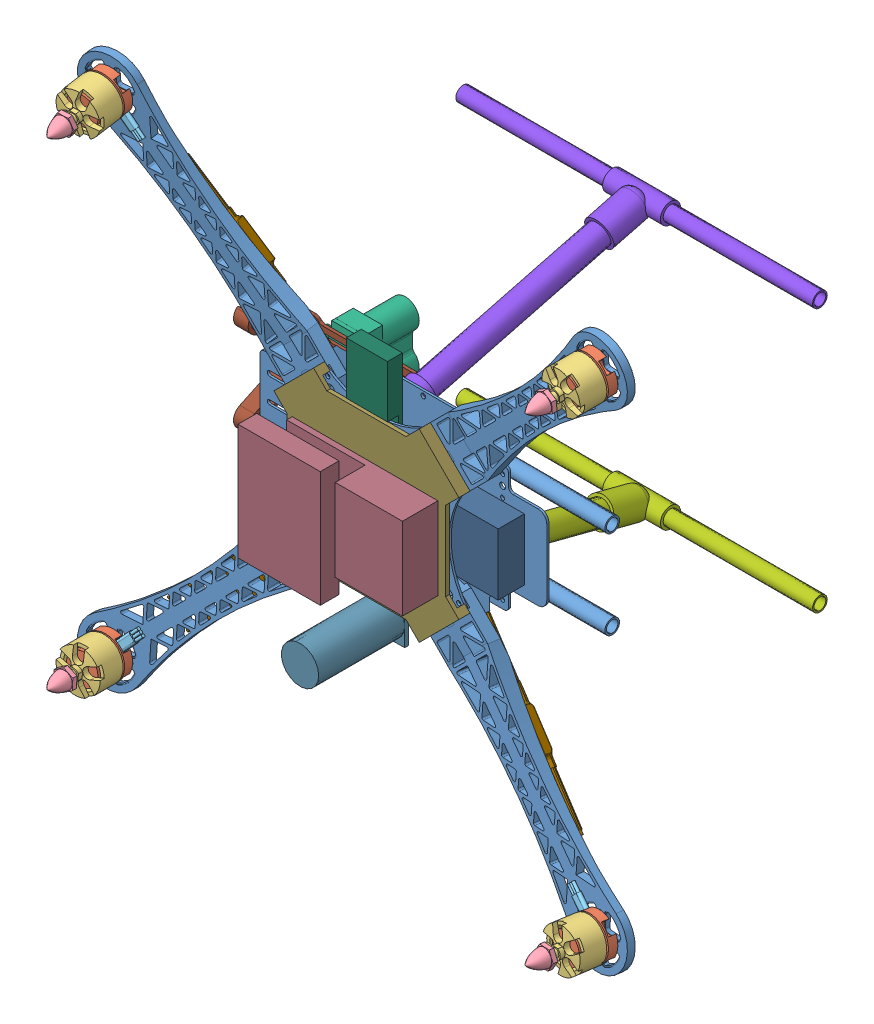
SolidWorks assembly Complete Drone Gazebo, configuration Default. Lengths in mm.
Overall size (374.52 411.37 390.68).
34 component instances, 15 part files, 50 mates.
Components (placement in the parent):
- S500 Frame-1: S500 Frame [Default] at (72.5801 224.1097 294.7299) size (374.52 374.52 61.06)
- User Library-emaxmodel-mt2213-1: User Library-emaxmodel-mt2213 [По умолчанию] at (238.5265 390.0562 331.8046) x (0.997236 0.002051 0.074267) z (0.007529 -0.997263 -0.073557) size (36.98 47 36.98)
  - User Library-emaxmodel-mt2213_emaxmodel-mt2213-stator-1: User Library-emaxmodel-mt2213_emaxmodel-mt2213-stator [По умолчанию] at origin size (28 21 28)
  - User Library-emaxmodel-mt2213_emaxmodel-mt2213-rotor-1: User Library-emaxmodel-mt2213_emaxmodel-mt2213-rotor [По умолчанию] at (0 7 0) x (0.999557 0 0.02976) z (-0.02976 0 0.999557) size (28 32 28)
  - User Library-emaxmodel-mt2213_emaxmodel-mt2213-cone-1: User Library-emaxmodel-mt2213_emaxmodel-mt2213-cone [По умолчанию] at (0 32 0) size (12 15 13.86)
  - User Library-emaxmodel-mt2213_wires-1: User Library-emaxmodel-mt2213_wires [По умолчанию] at (-15.8508 1.5 15.8508) x (0.707107 0 0.707107) z (-0.707107 0 0.707107) size (7 3 19)
- User Library-emaxmodel-mt2213-2: User Library-emaxmodel-mt2213 [По умолчанию] at (-93.3664 58.1632 331.8046) x (-0.996096 -0.042797 0.07721) z (-0.048269 0.996346 -0.070461) size (36.98 47 36.98)
  - User Library-emaxmodel-mt2213_emaxmodel-mt2213-stator-1: User Library-emaxmodel-mt2213_emaxmodel-mt2213-stator [По умолчанию] at origin size (28 21 28)
  - User Library-emaxmodel-mt2213_emaxmodel-mt2213-rotor-1: User Library-emaxmodel-mt2213_emaxmodel-mt2213-rotor [По умолчанию] at (0 7 0) x (0.999557 0 0.02976) z (-0.02976 0 0.999557) size (28 32 28)
  - User Library-emaxmodel-mt2213_emaxmodel-mt2213-cone-1: User Library-emaxmodel-mt2213_emaxmodel-mt2213-cone [По умолчанию] at (0 32 0) size (12 15 13.86)
  - User Library-emaxmodel-mt2213_wires-1: User Library-emaxmodel-mt2213_wires [По умолчанию] at (-15.8508 1.5 15.8508) x (0.707107 0 0.707107) z (-0.707107 0 0.707107) size (7 3 19)
- User Library-emaxmodel-mt2213-3: User Library-emaxmodel-mt2213 [По умолчанию] at (-93.3664 390.0562 331.8046) x (0.025833 0.997057 0.072181) z (0.99693 -0.020357 -0.075605) size (36.98 47 36.98)
  - User Library-emaxmodel-mt2213_emaxmodel-mt2213-stator-1: User Library-emaxmodel-mt2213_emaxmodel-mt2213-stator [По умолчанию] at origin size (28 21 28)
  - User Library-emaxmodel-mt2213_emaxmodel-mt2213-rotor-1: User Library-emaxmodel-mt2213_emaxmodel-mt2213-rotor [По умолчанию] at (0 7 0) x (0.999557 0 0.02976) z (-0.02976 0 0.999557) size (28 32 28)
  - User Library-emaxmodel-mt2213_emaxmodel-mt2213-cone-1: User Library-emaxmodel-mt2213_emaxmodel-mt2213-cone [По умолчанию] at (0 32 0) size (12 15 13.86)
  - User Library-emaxmodel-mt2213_wires-1: User Library-emaxmodel-mt2213_wires [По умолчанию] at (-15.8508 1.5 15.8508) x (0.707107 0 0.707107) z (-0.707107 0 0.707107) size (7 3 19)
- User Library-emaxmodel-mt2213-4: User Library-emaxmodel-mt2213 [По умолчанию] at (238.5265 58.1632 331.8046) x (0.007659 -0.997178 0.074679) z (-0.997235 -0.013136 -0.073138) size (36.98 47 36.98)
  - User Library-emaxmodel-mt2213_emaxmodel-mt2213-stator-1: User Library-emaxmodel-mt2213_emaxmodel-mt2213-stator [По умолчанию] at origin size (28 21 28)
  - User Library-emaxmodel-mt2213_emaxmodel-mt2213-rotor-1: User Library-emaxmodel-mt2213_emaxmodel-mt2213-rotor [По умолчанию] at (0 7 0) x (0.999557 0 0.02976) z (-0.02976 0 0.999557) size (28 32 28)
  - User Library-emaxmodel-mt2213_emaxmodel-mt2213-cone-1: User Library-emaxmodel-mt2213_emaxmodel-mt2213-cone [По умолчанию] at (0 32 0) size (12 15 13.86)
  - User Library-emaxmodel-mt2213_wires-1: User Library-emaxmodel-mt2213_wires [По умолчанию] at (-15.8508 1.5 15.8508) x (0.707107 0 0.707107) z (-0.707107 0 0.707107) size (7 3 19)
- User Library-LIDAR-Lite_v3-1: User Library-LIDAR-Lite_v3 [Default] at (-16.6199 221.1097 248.205) x (0 -1 0) z (0 0 -1) size (48.5 35.6 40)
- Drone Legs-1: Drone Legs [Default] at (195.2301 134.5438 138.1528) x (0 -0.967884 0.251398) z (-1 0 0) size (19.56 171.15 242.57)
- Drone Legs Right-1: Drone Legs Right [Default] at (195.2301 313.6756 138.1528) x (0 -0.967884 -0.251398) z (-1 0 0) size (19.56 171.15 242.57)
- 30A ESC-1: 30A ESC [Default] at (166.8316 147.9576 305.3085) x (0.707107 0.707107 0) z (0.69963 -0.69963 0.145038) size (28.83 9.95 119.13)
- 30A ESC-2: 30A ESC [Default] at (-3.8513 129.5788 305.3664) x (0.707107 -0.707107 0) z (-0.69963 -0.69963 0.145038) size (28.83 9.95 119.13)
- 30A ESC-3: 30A ESC [Default] at (-4.7202 319.5053 311.4505) x (0.707107 0.707107 0) z (-0.69963 0.69963 0.145038) size (28.83 9.95 119.13)
- 30A ESC-4: 30A ESC [Default] at (167.8781 301.3124 311.4303) x (0.707107 -0.707107 0) z (0.69963 0.69963 0.145038) size (28.83 9.95 119.13)
- LiPO Battery-1: LiPO Battery [Default] at (83.8871 224.0547 296.2299) size (136.91 41.91 17.78)
- S500 Frame - Copy-1: S500 Frame - Copy [Default] at (-56.5902 224.1097 294.7299) size (100 71.1 41.02)
- Gazebo Drone Mount-1: Gazebo Drone Mount [Default] at (72.5801 224.039 323.8499) x (-0.707107 0.707107 0) z (0 0 -1) size (139.7 139.7 7.62)
- Electronics gazebo-1: Electronics gazebo [Default] at (71.6753 223.0343 323.8499) x (0 -1 0) z (0 0 1) size (78.74 101.6 34.29)
- RTK  Antennae Gazebo-1: RTK  Antennae Gazebo [Default] at (76.7679 163.0462 312.1899) x (-1 0 0) z (0 0 1) size (25.4 38.1 60.96)
- Gazebo xbee-1: Gazebo xbee [Default] at (71.4223 291.4188 312.1899) size (27.94 45.72 10.16)
Mates (geometry in assembly coordinates):
- Concentric8: concentric aligned: circle of S500 Frame-1; circle of User Library-emaxmodel-mt2213-3/User Library-emaxmodel-mt2213_emaxmodel-mt2213-stator-1
- Coincident4: coincident anti-aligned: plane of S500 Frame-1 through (-121.5693 391.389 333.9997) normal (0.073913 -0.073913 0.994522); plane of User Library-emaxmodel-mt2213-3/User Library-emaxmodel-mt2213_emaxmodel-mt2213-stator-1 through (-93.3664 390.0562 331.8046) normal (-0.073913 0.073913 -0.994522)
- Concentric9: concentric aligned: circle of S500 Frame-1; circle of User Library-emaxmodel-mt2213-1/User Library-emaxmodel-mt2213_emaxmodel-mt2213-stator-1
- Coincident5: coincident anti-aligned: plane of S500 Frame-1 through (239.8594 418.2591 333.9997) normal (-0.073913 -0.073913 0.994522); plane of User Library-emaxmodel-mt2213-1/User Library-emaxmodel-mt2213_emaxmodel-mt2213-stator-1 through (238.5265 390.0562 331.8046) normal (0.073913 0.073913 -0.994522)
- Concentric10: concentric aligned: circle of S500 Frame-1; circle of User Library-emaxmodel-mt2213-4/User Library-emaxmodel-mt2213_emaxmodel-mt2213-stator-1
- Coincident7: coincident anti-aligned: plane of S500 Frame-1 through (266.7295 56.8304 333.9997) normal (-0.073913 0.073913 0.994522); plane of User Library-emaxmodel-mt2213-4/User Library-emaxmodel-mt2213_emaxmodel-mt2213-stator-1 through (238.5265 58.1632 331.8046) normal (0.073913 -0.073913 -0.994522)
- Concentric11: concentric aligned: circle of S500 Frame-1; circle of User Library-emaxmodel-mt2213-2/User Library-emaxmodel-mt2213_emaxmodel-mt2213-stator-1
- Coincident8: coincident anti-aligned: plane of S500 Frame-1 through (-94.6993 29.9603 333.9997) normal (0.073913 0.073913 0.994522); plane of User Library-emaxmodel-mt2213-2/User Library-emaxmodel-mt2213_emaxmodel-mt2213-stator-1 through (-93.3664 58.1632 331.8046) normal (-0.073913 -0.073913 -0.994522)
- Coincident17: coincident anti-aligned: plane of S500 Frame-1 through (70.0801 224.1097 294.7299) normal (0 0 -1); plane of Drone Legs-1 through (-47.3399 185.3167 294.7299) normal (0 0 1)
- Parallel6: parallel aligned: plane of S500 Frame-1 through (-52.4199 254.1097 281.7299) normal (-1 0 0); plane of Drone Legs-1 through (-47.3399 134.5438 138.1528) normal (-1 0 0)
- Tangent5: tangent: line of S500 Frame-1 through (35.9491 165.1097 294.7299) axis (1 0 0); curve of Drone Legs-1
- Distance11: distance = 5.08 mm aligned: plane of S500 Frame-1 through (-52.4199 194.1097 281.7299) normal (-1 0 0); plane of Drone Legs-1 through (-47.3399 134.5438 138.1528) normal (-1 0 0)
- Coincident20: coincident anti-aligned: plane of S500 Frame-1 through (70.0801 224.1097 294.7299) normal (0 0 -1); plane of Drone Legs Right-1 through (-47.3399 283.1097 294.7299) normal (0 0 1)
- Distance12: distance = 5.08 mm aligned: plane of Drone Legs Right-1 through (-47.3399 313.6756 138.1528) normal (-1 0 0); plane of S500 Frame-1 through (-52.4199 254.1097 281.7299) normal (-1 0 0)
- Tangent6: tangent: line of S500 Frame-1 through (109.211 283.1097 294.7299) axis (-1 0 0); curve of Drone Legs Right-1
- Coincident21: coincident anti-aligned: plane of 30A ESC-4 through (167.8781 301.3124 311.4303) normal (-0.102557 -0.102557 0.989426); plane of S500 Frame-1 through (120.3098 298.7095 306.2299) normal (0.102557 0.102557 -0.989426)
- Tangent7: tangent anti-aligned: cylinder of S500 Frame-1 through (430.5016 85.5638 323.4423) axis (-0.073913 -0.073913 0.994522) radius 339.0556; plane of 30A ESC-4 through (160.5898 295.1489 304.1315) normal (0.707107 -0.707107 0)
- Lock1: lock: unknown of S500 Frame-1; unknown of 30A ESC-4
- Coincident26: coincident anti-aligned: plane of S500 Frame-1 through (-2.0197 271.8394 306.2299) normal (-0.102557 0.102557 -0.989426); plane of 30A ESC-3 through (-4.7202 319.5053 311.4505) normal (0.102557 -0.102557 0.989426)
- Tangent8: tangent anti-aligned: cylinder of S500 Frame-1 through (211.126 582.0313 323.4423) axis (0.073913 -0.073913 0.994522) radius 339.0556; plane of 30A ESC-3 through (1.4433 312.217 304.1517) normal (0.707107 0.707107 0)
- Lock2: lock: unknown of S500 Frame-1; unknown of 30A ESC-3
- Coincident27: coincident anti-aligned: plane of 30A ESC-1 through (166.2325 148.5568 311.0887) normal (-0.102557 0.102557 0.989426); plane of S500 Frame-1 through (147.1798 176.38 306.2299) normal (0.102557 -0.102557 -0.989426)
- Tangent10: tangent anti-aligned: cylinder of S500 Frame-1 through (-65.9659 -133.8119 323.4423) axis (-0.073913 0.073913 0.994522) radius 339.0556; plane of 30A ESC-1 through (141.3724 138.3468 309.5702) normal (-0.707107 -0.707107 0)
- Lock3: lock: unknown of S500 Frame-1; unknown of 30A ESC-1
- Coincident29: coincident anti-aligned: plane of S500 Frame-1 through (24.8503 149.5099 306.2299) normal (-0.102557 -0.102557 -0.989426); plane of 30A ESC-2 through (-3.2522 130.1779 311.1466) normal (0.102557 0.102557 0.989426)
- Tangent13: tangent anti-aligned: cylinder of S500 Frame-1 through (-285.3415 362.6556 323.4423) axis (0.073913 0.073913 0.994522) radius 339.0556; plane of 30A ESC-2 through (-13.4622 155.038 309.6281) normal (-0.707107 0.707107 0)
- Lock4: lock: unknown of S500 Frame-1; unknown of 30A ESC-2
- Coincident30: coincident anti-aligned: plane of S500 Frame-1 through (70.0801 224.1097 296.2299) normal (0 0 1); plane of LiPO Battery-1 through (83.8871 224.0547 296.2299) normal (0 0 -1)
- Distance15: distance = 15.24 mm aligned: plane of LiPO Battery-1 through (152.3401 203.0997 314.0099) normal (1 0 0); plane of S500 Frame-1 through (167.5801 195.6097 294.7299) normal (1 0 0)
- Distance16: distance = 38.1 mm aligned: plane of LiPO Battery-1 through (152.3401 245.0097 314.0099) normal (0 1 0); plane of S500 Frame-1 through (110.4537 283.1097 294.7299) normal (0 1 0)
- Concentric19: concentric anti-aligned: circle of S500 Frame-1; circle of S500 Frame - Copy-1
- Concentric20: concentric anti-aligned: circle of S500 Frame-1; circle of S500 Frame - Copy-1
- Coincident36: coincident aligned: plane of S500 Frame-1 through (-52.4199 254.1097 281.7299) normal (-1 0 0); plane of S500 Frame - Copy-1 through (-52.4199 224.1097 269.7174) normal (-1 0 0)
- Coincident39: coincident anti-aligned: plane of User Library-LIDAR-Lite_v3-1 through (-16.6199 221.1097 248.205) normal (0 0 1); plane of S500 Frame - Copy-1 through (-12.4199 224.1097 248.205) normal (0 0 -1)
- Concentric27: concentric anti-aligned: circle of User Library-LIDAR-Lite_v3-1; circle of S500 Frame - Copy-1
- Parallel8: parallel aligned: plane of User Library-LIDAR-Lite_v3-1 through (-21.6199 216.8644 233.605) normal (-1 0 0); plane of S500 Frame - Copy-1 through (-62.4199 204.1097 249.205) normal (-1 0 0)
- Coincident40: coincident anti-aligned: plane of S500 Frame-1 through (121.724 174.9658 316.2299) normal (0 0 1); plane of Gazebo Drone Mount-1 through (72.5801 224.039 316.2299) normal (0 0 -1)
- Parallel9: parallel: line of S500 Frame-1 through (133.7448 189.815 316.2299) axis (-0.707107 -0.707107 0); plane of Gazebo Drone Mount-1 through (9.7183 259.96 321.3099) normal (-0.707107 0.707107 0)
- Coincident42: coincident aligned: plane of S500 Frame-1 through (101.2179 279.6176 314.7299) normal (-0.707107 0.707107 0); plane of Gazebo Drone Mount-1 through (99.5208 277.9205 321.3099) normal (-0.707107 0.707107 0)
- Parallel10: parallel aligned: plane of S500 Frame-1 through (43.9422 168.6018 314.7299) normal (0.707107 -0.707107 0); plane of Gazebo Drone Mount-1 through (45.6393 170.1575 321.3099) normal (0.707107 -0.707107 0)
- Coincident44: coincident aligned: plane of S500 Frame-1 through (128.0879 195.4719 314.7299) normal (0.707107 0.707107 0); plane of Gazebo Drone Mount-1 through (126.4616 197.0982 321.3099) normal (0.707107 0.707107 0)
- Coincident46: coincident anti-aligned: plane of Gazebo Drone Mount-1 through (72.5801 224.039 323.8499) normal (0 0 1); plane of Electronics gazebo-1 through (71.6753 223.0343 323.8499) normal (0 0 -1)
- Parallel12: parallel aligned: plane of Gazebo Drone Mount-1 through (126.4616 197.0982 321.3099) normal (1 0 0); plane of Electronics gazebo-1 through (121.2053 195.0943 327.6599) normal (1 0 0)
- Lock5: lock: unknown of Gazebo Drone Mount-1; unknown of Electronics gazebo-1
- Coincident48: coincident anti-aligned: plane of S500 Frame-1 through (72.5801 224.1097 314.7299) normal (0 0 -1); plane of RTK  Antennae Gazebo-1 through (76.7679 163.0462 314.7299) normal (0 0 1)
- Parallel13: parallel aligned: plane of Gazebo Drone Mount-1 through (45.6393 170.1575 321.3099) normal (0 -1 0); plane of RTK  Antennae Gazebo-1 through (64.0679 143.9962 314.7299) normal (0 -1 0)
- Lock6: lock: unknown of Gazebo Drone Mount-1; unknown of RTK  Antennae Gazebo-1
- Coincident50: coincident anti-aligned: plane of S500 Frame-1 through (72.5801 224.1097 314.7299) normal (0 0 -1); plane of Gazebo xbee-1 through (71.4223 291.4188 314.7299) normal (0 0 1)
- Parallel14: parallel aligned: plane of Gazebo Drone Mount-1 through (99.5208 277.9205 321.3099) normal (0 1 0); plane of Gazebo xbee-1 through (85.3923 314.2788 314.7299) normal (0 1 0)
- Lock7: lock: unknown of Gazebo Drone Mount-1; unknown of Gazebo xbee-1
